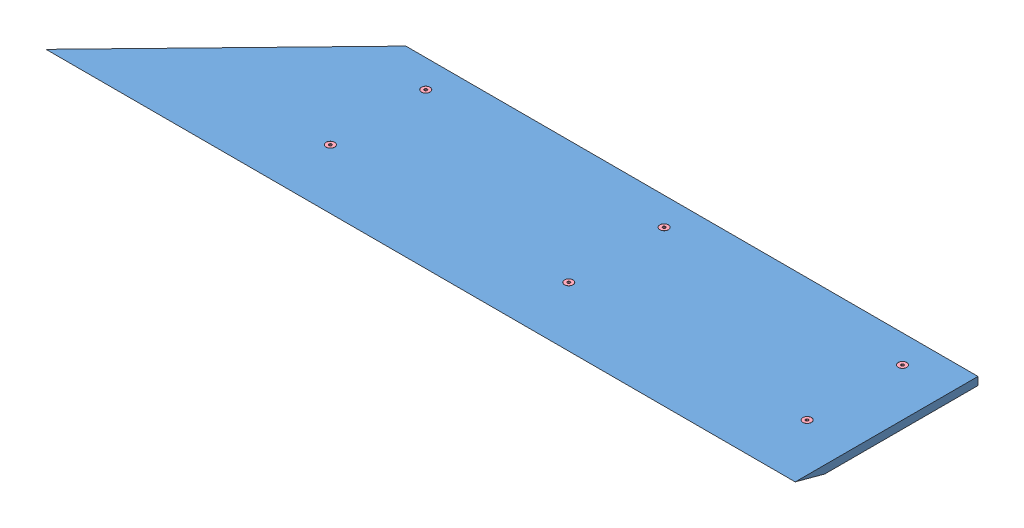
SolidWorks assembly GE-19057, configuration Default. Lengths in mm.
Overall size (1197.46 51.01 298.45).
16 component instances, 4 part files, 30 mates.
Components (placement in the parent):
- GE-19056-1: GE-19056 [Default] at (-11.9112 -4.3385 -141.1312) size (1197.46 12.7 292.1)
- GE-19055-1: GE-19055 [Default] at (-415.1362 -42.4385 -142.706) size (44.45 38.1 228.6)
- GE-19055-2: GE-19055 [Default] at (-34.1362 -42.4385 -142.706) size (44.45 38.1 228.6)
- GE-19055-3: GE-19055 [Default] at (346.8638 -42.4385 -142.706) size (44.45 38.1 228.6)
- nylock_.25_20-1: nylock_.25_20 [Default] at (369.0888 -9.1137 -96.6812) x (-0.837169 0 -0.546944) z (-0.546944 0 0.837169) size (11.11 7.94 12.83)
- nylock_.25_20-2: nylock_.25_20 [Default] at (369.0888 -9.1137 55.7188) x (-0.925243 0 -0.379375) z (-0.379375 0 0.925243) size (11.11 7.94 12.83)
- nylock_.25_20-3: nylock_.25_20 [Default] at (-11.9112 -9.1137 -96.6812) x (-0.985271 0 -0.170998) z (-0.170998 0 0.985271) size (11.11 7.94 12.83)
- nylock_.25_20-4: nylock_.25_20 [Default] at (-11.9112 -9.1137 55.7188) x (-0.997902 0 0.064746) z (0.064746 0 0.997902) size (11.11 7.94 12.83)
- nylock_.25_20-5: nylock_.25_20 [Default] at (-392.9112 -9.1137 -96.6812) x (-0.953572 0 0.301166) z (0.301166 0 0.953572) size (11.11 7.94 12.83)
- nylock_.25_20-6: nylock_.25_20 [Default] at (-392.9112 -9.1137 55.7188) x (-0.86157 0 0.507639) z (0.507639 0 0.86157) size (11.11 7.94 12.83)
- flat_hex_.25_20_1-1: flat_hex_.25_20_1 [91253A542] at (369.0888 8.3615 -96.6812) x (1 0 0) z (0 1 0) size (13.49 13.49 25.61)
- flat_hex_.25_20_1-2: flat_hex_.25_20_1 [91253A542] at (369.0888 8.3615 55.7188) x (0.982082 0 -0.188455) z (0 1 0) size (13.49 13.49 25.61)
- flat_hex_.25_20_1-3: flat_hex_.25_20_1 [91253A542] at (-11.9112 8.3615 -96.6812) x (0.918365 0 -0.395734) z (0 1 0) size (13.49 13.49 25.61)
- flat_hex_.25_20_1-4: flat_hex_.25_20_1 [91253A542] at (-11.9112 8.3615 55.7188) x (0.8 0 -0.6) z (0 1 0) size (13.49 13.49 25.61)
- flat_hex_.25_20_1-5: flat_hex_.25_20_1 [91253A542] at (-392.9112 8.3615 55.7188) x (0.63358 0 -0.773678) z (0 1 0) size (13.49 13.49 25.61)
- flat_hex_.25_20_1-6: flat_hex_.25_20_1 [91253A542] at (-392.9112 8.3615 -96.6812) x (0.443629 0 -0.896211) z (0 1 0) size (13.49 13.49 25.61)
Mates (geometry in assembly coordinates):
- Coincident1: coincident: plane of GE-19056-1 through (-11.9112 -4.3385 -141.1312) normal (0 -1 0); plane of GE-19055-1 through (-370.6862 -4.3385 81.1188) normal (0 1 0)
- Concentric1: concentric: cylinder of GE-19056-1 through (-392.9112 8.3615 -96.6812) axis (0 1 0) radius 3.5712; cylinder of GE-19055-1 through (-392.9112 -42.4385 -96.6812) axis (0 1 0) radius 3.3655
- Coincident2: coincident: plane of GE-19056-1 through (-11.9112 -4.3385 -141.1312) normal (0 -1 0); plane of GE-19055-2 through (10.3138 -4.3385 81.1188) normal (0 1 0)
- Concentric2: concentric: cylinder of GE-19056-1 through (-11.9112 8.3615 -96.6812) axis (0 1 0) radius 3.5712; cylinder of GE-19055-2 through (-11.9112 -42.4385 -96.6812) axis (0 1 0) radius 3.3655
- Coincident3: coincident: plane of GE-19056-1 through (-11.9112 -4.3385 -141.1312) normal (0 -1 0); plane of GE-19055-3 through (391.3138 -4.3385 81.1188) normal (0 1 0)
- Concentric3: concentric: cylinder of GE-19056-1 through (369.0888 8.3615 -96.6812) axis (0 1 0) radius 3.5712; cylinder of GE-19055-3 through (369.0888 -42.4385 -96.6812) axis (0 1 0) radius 3.3655
- Concentric4: concentric: cylinder of assembly; cylinder of assembly; cylinder of GE-19055-3 through (369.0888 -42.4385 -96.6812) axis (0 1 0) radius 3.3655; cylinder of nylock_.25_20-1 through (369.0888 -9.1137 -96.6812) axis (0 -1 0) radius 3.175
- Coincident4: coincident: plane of assembly; plane of assembly; plane of GE-19055-3 through (391.3138 -9.1137 -142.706) normal (0 -1 0); plane of nylock_.25_20-1 through (369.0888 -9.1137 -96.6812) normal (0 1 0)
- Concentric5: concentric: cylinder of assembly; cylinder of assembly; cylinder of GE-19055-3 through (369.0888 -42.4385 55.7188) axis (0 1 0) radius 3.3655; cylinder of nylock_.25_20-2 through (369.0888 -9.1137 55.7188) axis (0 -1 0) radius 3.175
- Coincident5: coincident: plane of assembly; plane of assembly; plane of GE-19055-3 through (391.3138 -9.1137 -142.706) normal (0 -1 0); plane of nylock_.25_20-2 through (369.0888 -9.1137 55.7188) normal (0 1 0)
- Coincident6: coincident: plane of assembly; plane of assembly; plane of GE-19055-3 through (391.3138 -9.1137 -142.706) normal (0 -1 0); plane of nylock_.25_20-3 through (-11.9112 -9.1137 -96.6812) normal (0 1 0)
- Concentric6: concentric: cylinder of assembly; cylinder of assembly; cylinder of GE-19055-2 through (-11.9112 -42.4385 -96.6812) axis (0 1 0) radius 3.3655; cylinder of nylock_.25_20-3 through (-11.9112 -9.1137 -96.6812) axis (0 -1 0) radius 3.175
- Coincident7: coincident: plane of assembly; plane of assembly; plane of GE-19055-3 through (391.3138 -9.1137 -142.706) normal (0 -1 0); plane of nylock_.25_20-4 through (-11.9112 -9.1137 55.7188) normal (0 1 0)
- Concentric7: concentric: cylinder of assembly; cylinder of assembly; cylinder of GE-19055-2 through (-11.9112 -42.4385 55.7188) axis (0 1 0) radius 3.3655; cylinder of nylock_.25_20-4 through (-11.9112 -9.1137 55.7188) axis (0 -1 0) radius 3.175
- Coincident8: coincident: plane of assembly; plane of assembly; plane of GE-19055-3 through (391.3138 -9.1137 -142.706) normal (0 -1 0); plane of nylock_.25_20-5 through (-392.9112 -9.1137 -96.6812) normal (0 1 0)
- Concentric8: concentric: cylinder of assembly; cylinder of assembly; cylinder of GE-19055-1 through (-392.9112 -42.4385 -96.6812) axis (0 1 0) radius 3.3655; cylinder of nylock_.25_20-5 through (-392.9112 -9.1137 -96.6812) axis (0 -1 0) radius 3.175
- Coincident9: coincident: plane of assembly; plane of assembly; plane of GE-19055-3 through (391.3138 -9.1137 -142.706) normal (0 -1 0); plane of nylock_.25_20-6 through (-392.9112 -9.1137 55.7188) normal (0 1 0)
- Concentric9: concentric: cylinder of assembly; cylinder of assembly; cylinder of GE-19055-1 through (-392.9112 -42.4385 55.7188) axis (0 1 0) radius 3.3655; cylinder of nylock_.25_20-6 through (-392.9112 -9.1137 55.7188) axis (0 -1 0) radius 3.175
- Concentric10: concentric: cylinder of GE-19056-1 through (369.0888 8.3615 -96.6812) axis (0 1 0) radius 3.5712; cylinder of flat_hex_.25_20_1-1 through (369.0888 -17.0385 -96.6812) axis (0 -1 0) radius 3.175
- Coincident11: coincident: plane of GE-19056-1 through (-11.9112 8.3615 -141.1312) normal (0 1 0); plane of flat_hex_.25_20_1-1 through (369.0888 8.3615 -93.5062) normal (0 1 0)
- Concentric11: concentric: cylinder of GE-19056-1 through (369.0888 8.3615 55.7188) axis (0 1 0) radius 3.5712; cylinder of flat_hex_.25_20_1-2 through (369.0888 -17.0385 55.7188) axis (0 -1 0) radius 3.175
- Coincident12: coincident: plane of GE-19056-1 through (-11.9112 8.3615 -141.1312) normal (0 1 0); plane of flat_hex_.25_20_1-2 through (369.6871 8.3615 58.8369) normal (0 1 0)
- Coincident13: coincident: plane of GE-19056-1 through (-11.9112 8.3615 -141.1312) normal (0 1 0); plane of flat_hex_.25_20_1-3 through (-10.6548 8.3615 -93.7654) normal (0 1 0)
- Concentric12: concentric: cylinder of GE-19056-1 through (-11.9112 8.3615 -96.6812) axis (0 1 0) radius 3.5712; cylinder of flat_hex_.25_20_1-3 through (-11.9112 -17.0385 -96.6812) axis (0 -1 0) radius 3.175
- Coincident14: coincident: plane of GE-19056-1 through (-11.9112 8.3615 -141.1312) normal (0 1 0); plane of flat_hex_.25_20_1-4 through (-10.0062 8.3615 58.2588) normal (0 1 0)
- Concentric13: concentric: cylinder of GE-19056-1 through (-11.9112 8.3615 55.7188) axis (0 1 0) radius 3.5712; cylinder of flat_hex_.25_20_1-4 through (-11.9112 -17.0385 55.7188) axis (0 -1 0) radius 3.175
- Coincident15: coincident: plane of GE-19056-1 through (-11.9112 8.3615 -141.1312) normal (0 1 0); plane of flat_hex_.25_20_1-5 through (-390.4548 8.3615 57.7304) normal (0 1 0)
- Concentric14: concentric: cylinder of GE-19056-1 through (-392.9112 8.3615 55.7188) axis (0 1 0) radius 3.5712; cylinder of flat_hex_.25_20_1-5 through (-392.9112 -17.0385 55.7188) axis (0 -1 0) radius 3.175
- Coincident16: coincident: plane of GE-19056-1 through (-11.9112 8.3615 -141.1312) normal (0 1 0); plane of flat_hex_.25_20_1-6 through (-390.0658 8.3615 -95.2727) normal (0 1 0)
- Concentric15: concentric: cylinder of GE-19056-1 through (-392.9112 8.3615 -96.6812) axis (0 1 0) radius 3.5712; cylinder of flat_hex_.25_20_1-6 through (-392.9112 -17.0385 -96.6812) axis (0 -1 0) radius 3.175
